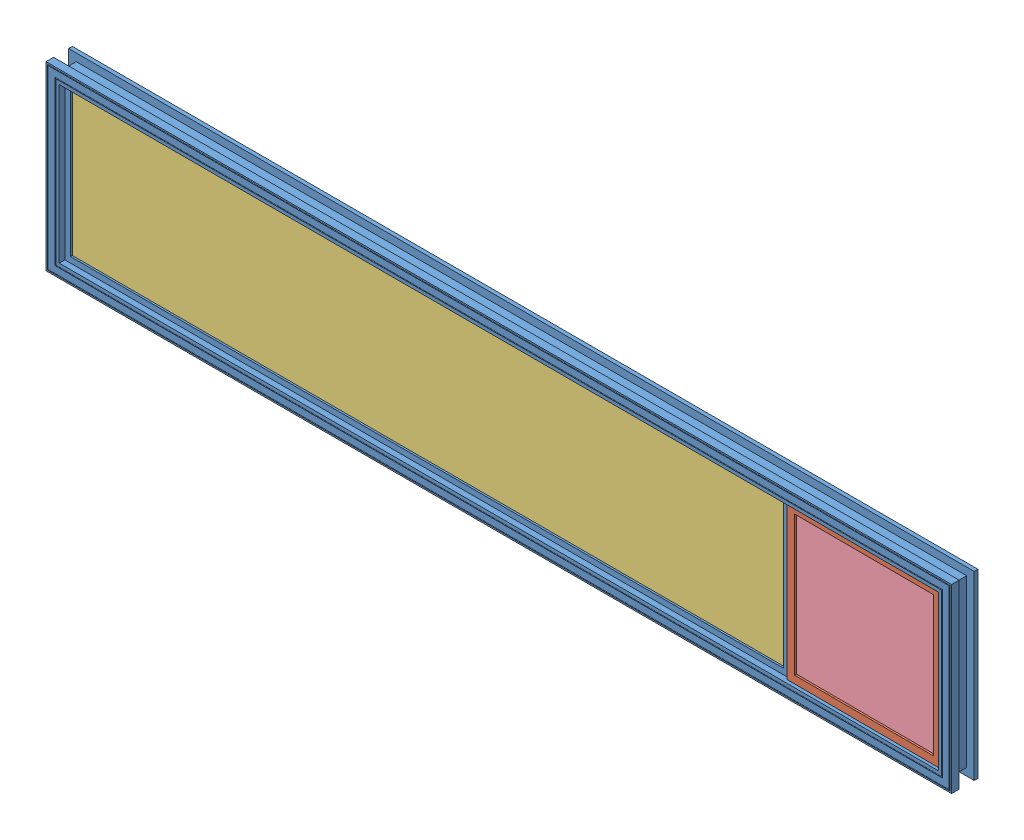
SolidWorks assembly 1050 WINDOW, configuration Default. Lengths in mm.
Overall size (1524 304.8 44.45).
6 component instances, 4 part files, 14 mates.
Components (placement in the parent):
- WINDOW MOLD-1: WINDOW MOLD [Default] at (629.7266 814.3811 1121.5523) size (1524 304.8 44.45)
- SMALL WINDOW MOLD-1: SMALL WINDOW MOLD [Default] at (1239.3634 814.3811 1130.655) x (0.999995 0 0.003245) z (-0.003245 0 0.999995) size (260.35 260.35 19.05)
- 1050 GLASS-1: 1050 GLASS [Default] at (500.3454 814.3811 1129.4898) size (1214.44 254 4.76)
- 1050 GLASS-2: 1050 GLASS [Default] at (501.1961 813.5304 1121.5523) size (1214.44 254 4.76)
- 1010 GLASS-1: 1010 GLASS [Default] at (1239.3376 814.3811 1138.5925) x (-0.999995 0 -0.003245) z (0.003245 0 -0.999995) size (241.3 241.3 4.76)
- 1010 GLASS-2: 1010 GLASS [Default] at (1239.3634 814.3811 1130.655) x (-0.999995 0 -0.003245) z (0.003245 0 -0.999995) size (241.3 241.3 4.76)
Mates (geometry in assembly coordinates):
- Coincident1: coincident anti-aligned: line of WINDOW MOLD-1 through (1369.5016 684.2061 1142.1898) axis (0 1 0); line of SMALL WINDOW MOLD-1 through (1369.5016 944.5561 1142.1898) axis (0 -1 0)
- Coincident2: coincident anti-aligned: plane of WINDOW MOLD-1 through (-132.2734 944.5561 1146.9523) normal (0 -1 0); plane of SMALL WINDOW MOLD-1 through (1108.5871 944.5561 1138.1682) normal (0 1 0)
- Coincident3: coincident anti-aligned: plane of WINDOW MOLD-1 through (-132.2734 935.0311 1134.2523) normal (0 0 -1); plane of 1050 GLASS-1 through (500.3454 814.3811 1134.2523) normal (0 0 1)
- Distance1: distance = 6.35 mm: line of WINDOW MOLD-1 through (-100.5234 693.7311 1134.2523) axis (0 1 0); line of 1050 GLASS-1 through (-106.8734 941.3811 1134.2523) axis (0 -1 0)
- Distance2: distance = 6.35 mm: line of WINDOW MOLD-1 through (1099.6266 693.7311 1134.2523) axis (-1 0 0); line of 1050 GLASS-1 through (-106.8734 687.3811 1134.2523) axis (1 0 0)
- Coincident8: coincident anti-aligned: plane of WINDOW MOLD-1 through (-132.2734 947.7311 1121.5523) normal (0 0 1); plane of 1050 GLASS-2 through (501.1961 813.5304 1121.5523) normal (0 0 -1)
- Distance3: distance = 6.35 mm: line of 1050 GLASS-2 through (1108.4149 940.5304 1121.5523) axis (-1 0 0); line of WINDOW MOLD-1 through (-100.5234 935.0311 1118.3773) axis (1 0 0)
- Distance4: distance = 6.35 mm: line of 1050 GLASS-2 through (-106.0226 940.5304 1121.5523) axis (0 -1 0); line of WINDOW MOLD-1 through (-100.5234 693.7311 1118.3773) axis (0 1 0)
- Coincident11: coincident anti-aligned: line of SMALL WINDOW MOLD-1 through (1121.8633 931.8561 1138.2113) axis (0.999995 0 0.003245); plane of 1010 GLASS-1 through (1239.3376 814.3811 1138.5925) normal (-0.003245 0 0.999995)
- Distance5: distance = 3.175 mm: line of SMALL WINDOW MOLD-1 through (1121.8633 696.9061 1138.2113) axis (0 1 0); line of 1010 GLASS-1 through (1118.6883 693.7311 1138.201) axis (0 1 0)
- Distance6: distance = 3.175 mm: line of SMALL WINDOW MOLD-1 through (1121.8633 931.8561 1138.2113) axis (0.999995 0 0.003245); line of 1010 GLASS-1 through (1118.6883 935.0311 1138.201) axis (0.999995 0 0.003245)
- Coincident14: coincident anti-aligned: plane of SMALL WINDOW MOLD-1 through (1108.6283 936.6186 1125.4683) normal (-0.003245 0 0.999995); plane of 1010 GLASS-2 through (1239.3788 814.3811 1125.8925) normal (0.003245 0 -0.999995)
- Distance7: distance = 3.175 mm: line of 1010 GLASS-2 through (1118.7295 935.0311 1125.501) axis (0.999995 0 0.003245); line of SMALL WINDOW MOLD-1 through (1121.9045 931.8561 1125.5113) axis (0.999995 0 0.003245)
- Distance9: distance = 3.175 mm: line of SMALL WINDOW MOLD-1 through (1356.8532 931.8561 1126.2737) axis (0 -1 0); plane of 1010 GLASS-2 through (1360.0282 693.7311 1126.284) normal (0.999995 0 0.003245)
